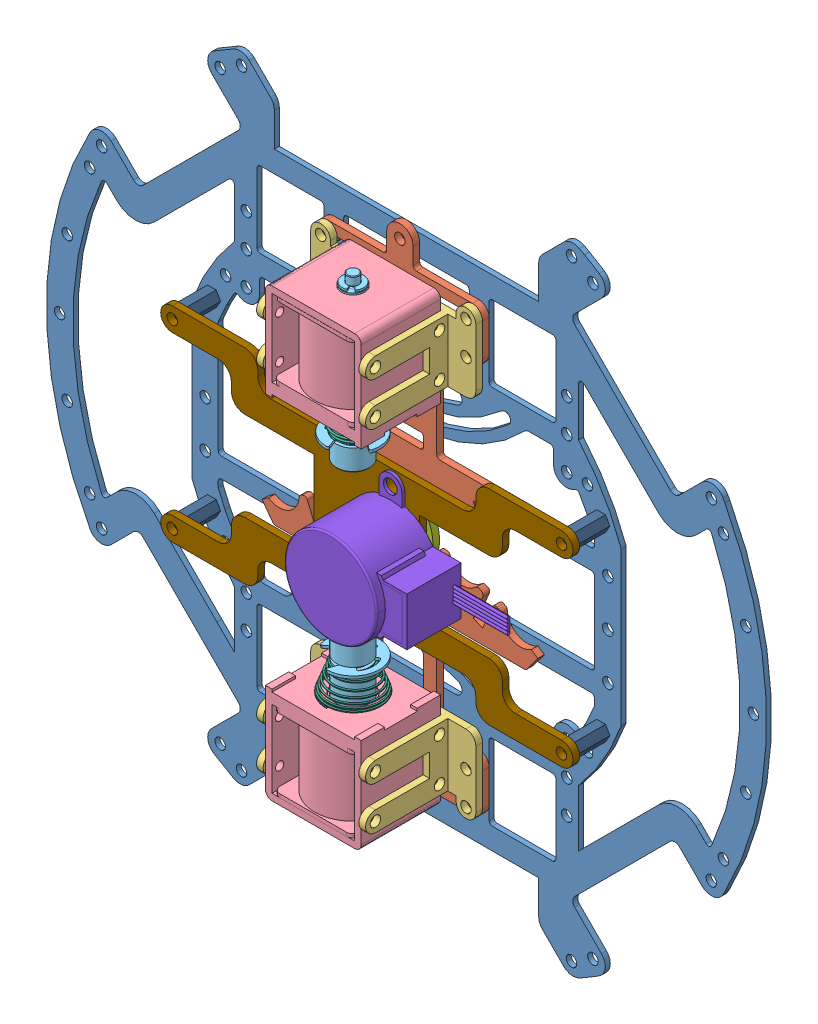
SolidWorks assembly Aimbot-G Test, configuration Default. Lengths in mm.
Overall size (218 192.21 35).
20 component instances, 10 part files, 35 mates.
Components (placement in the parent):
- Aimbot Mid-1: Aimbot Mid [Default] at (51.9891 116.4004 178.717) size (218 192.21 1.5)
- Aimbot Geneva 1-1: Aimbot Geneva 1 [Default] at (51.9891 43.4004 180.217) x (1 0 0) z (0 -1 0) size (83.44 2 74.25)
- Aimbot Geneva 1-2: Aimbot Geneva 1 [Default] at (51.9891 189.4004 182.217) x (1 0 0) z (0 1 0) size (83.44 2 74.25)
- CB1029 Kicker Stand-1: CB1029 Kicker Stand [Default] at (66.4891 162.9004 206.117) x (0 0 -1) z (1 0 0) size (26.9 23.5 50)
- CB1029 Kicker Stand-2: CB1029 Kicker Stand [Default] at (37.4891 69.9004 206.117) x (0 0 -1) z (-1 0 0) size (26.9 23.5 50)
- INPUT kicker-1: INPUT kicker [Default] at (49.1298 64.5038 196.6654) x (1 0 0) z (0 0 1) size (29 49.3 24.1)
  - Part5^w_cb1029A-1: Part5^w_cb1029A [Default] at (2.8592 11.2966 11.7516) size (29 29.6 24.1)
  - Part1^w_cb1029A_pl-1: Part1^w_cb1029A_pl [Default] at (2.8592 29.7903 -0.2484) x (-0.794223 0 -0.607626) z (0 1 0) size (16 14.34 49.3)
  - w_21053081-1: w_21053081 [Default] at (2.8631 13.1716 -0.3303) size (16.55 9.4 16.57)
- INPUT kicker-2: INPUT kicker [Default] at (54.8483 168.2969 196.6654) x (-1 0 0) z (0 0 1) size (29 49.3 24.1)
  - Part5^w_cb1029A-1: Part5^w_cb1029A [Default] at (2.8592 11.2966 11.7516) size (29 29.6 24.1)
  - Part1^w_cb1029A_pl-1: Part1^w_cb1029A_pl [Default] at (2.8592 29.7903 -0.2484) x (-0.794223 0 -0.607626) z (0 1 0) size (16 14.34 49.3)
  - w_21053081-1: w_21053081 [Default] at (2.8631 13.1716 -0.3303) size (16.55 9.4 16.57)
- Aimbot Geneva 2-2: Aimbot Geneva 2 [Default] at (51.9891 116.4004 184.217) x (-0.085569 -0.996332 0) z (0.996332 -0.085569 0) size (24 10.5 24)
- Stepper Motor-1: Stepper Motor [Default] at (59.9891 116.4004 211.217) x (0 -1 0) z (1 0 0) size (42 29 50.9)
- Stepper Stand-1: Stepper Stand [Default] at (-6.9228 88.9293 190.217) size (124.82 61.94 2)
- 10mm Standoff-1: 10mm Standoff [默认] at (-6.9228 88.9293 180.217) x (1 0 0) z (0 -1 0) size (5.31 10 4.6)
- 10mm Standoff-2: 10mm Standoff [默认] at (110.901 88.9293 180.217) x (1 0 0) z (0 -1 0) size (5.31 10 4.6)
- 10mm Standoff-3: 10mm Standoff [默认] at (110.901 143.8714 180.217) x (1 0 0) z (0 -1 0) size (5.31 10 4.6)
- 10mm Standoff-4: 10mm Standoff [默认] at (-6.9228 143.8714 180.217) x (1 0 0) z (0 -1 0) size (5.31 10 4.6)
Mates (geometry in assembly coordinates):
- Concentric1: concentric anti-aligned: cylinder of Aimbot Mid-1 through (51.9891 43.4004 178.717) axis (0 0 1) radius 1.5; cylinder of Aimbot Geneva 1-1 through (51.9891 43.4004 182.217) axis (0 0 -1) radius 1.6
- Concentric4: concentric aligned: cylinder of Aimbot Mid-1 through (51.9891 189.4004 178.717) axis (0 0 1) radius 1.5; cylinder of Aimbot Geneva 1-2 through (51.9891 189.4004 180.217) axis (0 0 1) radius 1.6
- Coincident4: coincident anti-aligned: plane of Aimbot Geneva 1-1 through (51.9891 43.4004 182.217) normal (0 0 1); plane of CB1029 Kicker Stand-2 through (37.4891 72.9004 182.217) normal (0 0 -1)
- Concentric7: concentric anti-aligned: cylinder of Aimbot Geneva 1-1 through (73.9891 62.4004 177.217) axis (0 0 1) radius 1.6; cylinder of CB1029 Kicker Stand-2 through (73.9891 62.4004 192.217) axis (0 0 -1) radius 1.6
- Concentric8: concentric anti-aligned: cylinder of Aimbot Geneva 1-1 through (29.9891 52.4004 177.217) axis (0 0 1) radius 1.6; cylinder of CB1029 Kicker Stand-2 through (29.9891 52.4004 192.217) axis (0 0 -1) radius 1.6
- Coincident5: coincident anti-aligned: plane of Aimbot Geneva 1-2 through (51.9891 189.4004 182.217) normal (0 0 1); plane of CB1029 Kicker Stand-1 through (66.4891 159.9004 182.217) normal (0 0 -1)
- Concentric9: concentric aligned: cylinder of Aimbot Geneva 1-2 through (73.9891 170.4004 185.217) axis (0 0 -1) radius 1.6; cylinder of CB1029 Kicker Stand-1 through (73.9891 170.4004 192.217) axis (0 0 -1) radius 1.6
- Concentric10: concentric aligned: cylinder of Aimbot Geneva 1-2 through (29.9891 170.4004 185.217) axis (0 0 -1) radius 1.6; cylinder of CB1029 Kicker Stand-1 through (29.9891 170.4004 192.217) axis (0 0 -1) radius 1.6
- Concentric14: concentric aligned: cylinder of CB1029 Kicker Stand-1 through (68.4891 175.9004 186.717) axis (-1 0 0) radius 1.6; cylinder of INPUT kicker-2/Part5^w_cb1029A-1 through (66.4891 175.9004 186.717) axis (-1 0 0) radius 1.25
- Concentric15: concentric aligned: cylinder of CB1029 Kicker Stand-1 through (68.4891 162.9004 186.717) axis (-1 0 0) radius 1.6; cylinder of INPUT kicker-2/Part5^w_cb1029A-1 through (66.4891 162.9004 186.717) axis (-1 0 0) radius 1.25
- Concentric16: concentric anti-aligned: cylinder of CB1029 Kicker Stand-2 through (68.4891 56.9004 186.717) axis (-1 0 0) radius 1.6; cylinder of INPUT kicker-1/Part5^w_cb1029A-1 through (64.4891 56.9004 186.717) axis (1 0 0) radius 1.25
- Concentric17: concentric anti-aligned: cylinder of CB1029 Kicker Stand-2 through (68.4891 69.9004 186.717) axis (-1 0 0) radius 1.6; cylinder of INPUT kicker-1/Part5^w_cb1029A-1 through (64.4891 69.9004 186.717) axis (1 0 0) radius 1.25
- Coincident8: coincident anti-aligned: plane of CB1029 Kicker Stand-2 through (66.4891 69.9004 206.117) normal (-1 0 0); plane of INPUT kicker-1/Part5^w_cb1029A-1 through (66.4891 50.9004 184.417) normal (1 0 0)
- Coincident9: coincident anti-aligned: plane of Aimbot Mid-1 through (51.9891 116.4004 180.217) normal (0 0 1); plane of Aimbot Geneva 1-1 through (51.9891 43.4004 180.217) normal (0 0 -1)
- Coincident10: coincident anti-aligned: plane of Aimbot Mid-1 through (51.9891 116.4004 180.217) normal (0 0 1); plane of Aimbot Geneva 1-2 through (51.9891 189.4004 180.217) normal (0 0 -1)
- Coincident11: coincident anti-aligned: plane of Aimbot Geneva 1-1 through (51.9891 43.4004 182.217) normal (0 0 1); plane of Aimbot Geneva 2-2 through (51.9891 116.4004 182.217) normal (0 0 -1)
- Concentric18: concentric anti-aligned: cylinder of Aimbot Mid-1 through (51.9891 116.4004 58.6468) axis (0 0 1) radius 1.6; cylinder of Aimbot Geneva 2-2 through (51.9891 116.4004 184.217) axis (0 0 -1) radius 1.6
- Concentric20: concentric anti-aligned: cylinder of Aimbot Geneva 2-2 through (51.9891 116.4004 189.217) axis (0 0 -1) radius 2.5; cylinder of Stepper Motor-1 through (51.9891 116.4004 165.1459) axis (0 0 1) radius 2.5
- Concentric25: concentric anti-aligned: cylinder of Aimbot Mid-1 through (-6.9228 143.8714 178.717) axis (0 0 1) radius 1.6; cylinder of Stepper Stand-1 through (-6.9228 143.8714 192.217) axis (0 0 -1) radius 1.6
- Concentric26: concentric anti-aligned: cylinder of Aimbot Mid-1 through (110.901 143.8714 178.717) axis (0 0 1) radius 1.6; cylinder of Stepper Stand-1 through (110.901 143.8714 192.217) axis (0 0 -1) radius 1.6
- Concentric27: concentric anti-aligned: cylinder of Aimbot Mid-1 through (110.901 88.9293 178.717) axis (0 0 1) radius 1.6; cylinder of Stepper Stand-1 through (110.901 88.9293 192.217) axis (0 0 -1) radius 1.6
- Concentric28: concentric anti-aligned: cylinder of Aimbot Mid-1 through (-6.9228 88.9293 178.717) axis (0 0 1) radius 1.6; cylinder of Stepper Stand-1 through (-6.9228 88.9293 192.217) axis (0 0 -1) radius 1.6
- Concentric29: concentric aligned: cylinder of Stepper Motor-1 through (59.9891 133.9004 193.117) axis (0 0 -1) radius 2.1; cylinder of Stepper Stand-1 through (59.9891 133.9004 192.217) axis (0 0 -1) radius 2.1
- Concentric30: concentric aligned: cylinder of Stepper Motor-1 through (59.9891 98.9004 193.117) axis (0 0 -1) radius 2.1; cylinder of Stepper Stand-1 through (59.9891 98.9004 192.217) axis (0 0 -1) radius 2.1
- Coincident19: coincident anti-aligned: plane of Stepper Motor-1 through (59.9891 116.4004 192.217) normal (0 0 -1); plane of Stepper Stand-1 through (-6.9228 88.9293 192.217) normal (0 0 1)
- Coincident20: coincident anti-aligned: plane of CB1029 Kicker Stand-1 through (37.4891 162.9004 206.117) normal (1 0 0); plane of INPUT kicker-2/Part5^w_cb1029A-1 through (37.4891 181.9004 184.417) normal (-1 0 0)
- Concentric31: concentric aligned: circle of Aimbot Mid-1; cylinder of 10mm Standoff-4 through (-6.9228 143.8714 185.217) axis (0 0 -1) radius 1.5
- Coincident22: coincident anti-aligned: plane of Aimbot Mid-1 through (51.9891 116.4004 180.217) normal (0 0 1); plane of 10mm Standoff-4 through (-6.9228 143.8714 180.217) normal (0 0 -1)
- Concentric32: concentric anti-aligned: cylinder of Aimbot Mid-1 through (-6.9228 88.9293 178.717) axis (0 0 1) radius 1.6; cylinder of 10mm Standoff-1 through (-6.9228 88.9293 185.217) axis (0 0 -1) radius 1.5
- Coincident23: coincident anti-aligned: plane of Aimbot Mid-1 through (51.9891 116.4004 180.217) normal (0 0 1); plane of 10mm Standoff-1 through (-6.9228 88.9293 180.217) normal (0 0 -1)
- Concentric33: concentric anti-aligned: cylinder of Aimbot Mid-1 through (110.901 143.8714 178.717) axis (0 0 1) radius 1.6; cylinder of 10mm Standoff-3 through (110.901 143.8714 185.217) axis (0 0 -1) radius 1.5
- Coincident24: coincident anti-aligned: plane of Aimbot Mid-1 through (51.9891 116.4004 180.217) normal (0 0 1); plane of 10mm Standoff-3 through (110.901 143.8714 180.217) normal (0 0 -1)
- Concentric34: concentric anti-aligned: cylinder of Aimbot Mid-1 through (110.901 88.9293 178.717) axis (0 0 1) radius 1.6; cylinder of 10mm Standoff-2 through (110.901 88.9293 185.217) axis (0 0 -1) radius 1.5
- Coincident25: coincident anti-aligned: plane of Aimbot Mid-1 through (51.9891 116.4004 180.217) normal (0 0 1); plane of 10mm Standoff-2 through (110.901 88.9293 180.217) normal (0 0 -1)
- Coincident26: coincident anti-aligned: plane of Stepper Stand-1 through (-6.9228 88.9293 190.217) normal (0 0 -1); plane of 10mm Standoff-2 through (110.901 88.9293 190.217) normal (0 0 1)
